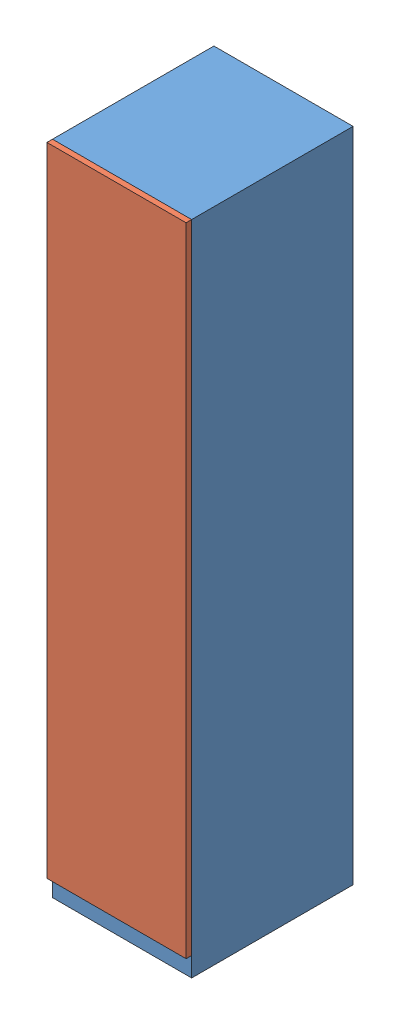
SolidWorks assembly PAX-Eingang, configuration Standard. Lengths in mm.
Overall size (500 2360 600).
8 component instances, 6 part files, 21 mates.
Components (placement in the parent):
- Pax-Korpus-Kleiderschrank-236-1: Pax-Korpus-Kleiderschrank-236 [Standard] at (-247.5936 -1124.7676 2360) size (500 2360 580)
- BALLSTAD-Tür-229-1: BALLSTAD-Tür-229 [Standard] at (-247.5936 90.2324 2650) size (500 2290 20)
- KOMPLEMENT-Regalbode-1: KOMPLEMENT-Regalbode [Standard] at (-247.5936 895.2324 2365) size (480 10 570)
- KOMPLEMENT-Kleiderstange-1: KOMPLEMENT-Kleiderstange [Standard] at (-487.5936 830.2324 2335) size (480 50 30)
- KOMPLEMENT-Regalbode-2: KOMPLEMENT-Regalbode [Standard] at (-247.5936 -434.7676 2365) size (480 10 570)
- KOMPLIMENT-Schublade-1: KOMPLIMENT-Schublade [Standard] at (-247.5936 -604.7676 2365) size (480 160 570)
- KOMPLEMENT-Netzdrahtkorb-1: KOMPLEMENT-Netzdrahtkorb [Standard] at (-247.5936 -894.7676 2365) size (480 160 570)
- KOMPLEMENT-Regalbode-3: KOMPLEMENT-Regalbode [Standard] at (-247.5936 -274.7676 2365) size (480 10 570)
Mates (geometry in assembly coordinates):
- Deckungsgleich1: coincident aligned: plane of Pax-Korpus-Kleiderschrank-236-1 through (-247.5936 1235.2324 2360) normal (0 1 0); plane of BALLSTAD-Tür-229-1 through (-497.5936 1235.2324 2670) normal (0 1 0)
- Deckungsgleich2: coincident anti-aligned: plane of Pax-Korpus-Kleiderschrank-236-1 through (-497.5936 -1114.7676 2650) normal (0 0 1); plane of BALLSTAD-Tür-229-1 through (-247.5936 90.2324 2650) normal (0 0 -1)
- Deckungsgleich3: coincident aligned: plane of Pax-Korpus-Kleiderschrank-236-1 through (-497.5936 -1114.7676 2650) normal (-1 0 0); plane of BALLSTAD-Tür-229-1 through (-497.5936 -1054.7676 2670) normal (-1 0 0)
- Deckungsgleich4: coincident anti-aligned: plane of Pax-Korpus-Kleiderschrank-236-1 through (-487.5936 1225.2324 2080) normal (0 0 1); plane of KOMPLEMENT-Regalbode-1 through (-487.5936 905.2324 2080) normal (0 0 -1)
- Deckungsgleich5: coincident anti-aligned: plane of Pax-Korpus-Kleiderschrank-236-1 through (-487.5936 1225.2324 2650) normal (1 0 0); plane of KOMPLEMENT-Regalbode-1 through (-487.5936 905.2324 2650) normal (-1 0 0)
- Abstand1: distance = 320 mm anti-aligned: plane of KOMPLEMENT-Regalbode-1 through (-247.5936 905.2324 2365) normal (0 1 0); plane of Pax-Korpus-Kleiderschrank-236-1 through (-247.5936 1225.2324 2360) normal (0 -1 0)
- Deckungsgleich7: coincident anti-aligned: plane of Pax-Korpus-Kleiderschrank-236-1 through (-487.5936 1225.2324 2650) normal (1 0 0); plane of KOMPLEMENT-Kleiderstange-1 through (-487.5936 830.2324 2335) normal (-1 0 0)
- Abstand2: distance = 50 mm anti-aligned: plane of KOMPLEMENT-Kleiderstange-1 through (-467.5936 845.2324 2320) normal (0 1 0); plane of KOMPLEMENT-Regalbode-1 through (-247.5936 895.2324 2365) normal (0 -1 0)
- Abstand3: distance = 300 mm aligned: plane of KOMPLEMENT-Kleiderstange-1 through (-467.5936 795.2324 2350) normal (0 0 1); plane of Pax-Korpus-Kleiderschrank-236-1 through (-497.5936 -1114.7676 2650) normal (0 0 1)
- Deckungsgleich10: coincident anti-aligned: plane of Pax-Korpus-Kleiderschrank-236-1 through (-487.5936 1225.2324 2080) normal (0 0 1); plane of KOMPLEMENT-Regalbode-2 through (-487.5936 -424.7676 2080) normal (0 0 -1)
- Deckungsgleich11: coincident anti-aligned: plane of Pax-Korpus-Kleiderschrank-236-1 through (-487.5936 1225.2324 2650) normal (1 0 0); plane of KOMPLEMENT-Regalbode-2 through (-487.5936 -424.7676 2650) normal (-1 0 0)
- Abstand4: distance = 1220 mm anti-aligned: plane of KOMPLEMENT-Kleiderstange-1 through (-467.5936 795.2324 2320) normal (0 -1 0); plane of KOMPLEMENT-Regalbode-2 through (-247.5936 -424.7676 2365) normal (0 1 0)
- Deckungsgleich13: coincident anti-aligned: plane of Pax-Korpus-Kleiderschrank-236-1 through (-487.5936 1225.2324 2080) normal (0 0 1); plane of KOMPLIMENT-Schublade-1 through (-487.5936 -594.7676 2080) normal (0 0 -1)
- Deckungsgleich14: coincident anti-aligned: plane of Pax-Korpus-Kleiderschrank-236-1 through (-487.5936 1225.2324 2650) normal (1 0 0); plane of KOMPLIMENT-Schublade-1 through (-487.5936 -594.7676 2650) normal (-1 0 0)
- Abstand5: distance = 10 mm anti-aligned: plane of KOMPLIMENT-Schublade-1 through (-247.5936 -444.7676 2365) normal (0 1 0); plane of KOMPLEMENT-Regalbode-2 through (-247.5936 -434.7676 2365) normal (0 -1 0)
- Deckungsgleich16: coincident anti-aligned: plane of Pax-Korpus-Kleiderschrank-236-1 through (-247.5936 -1054.7676 2360) normal (0 1 0); plane of KOMPLEMENT-Netzdrahtkorb-1 through (-247.5936 -1054.7676 2365) normal (0 -1 0)
- Deckungsgleich17: coincident: plane of Pax-Korpus-Kleiderschrank-236-1 through (-487.5936 1225.2324 2650) normal (1 0 0); line of KOMPLEMENT-Netzdrahtkorb-1 through (-487.5936 -894.7676 2080) axis (0 0 1)
- Deckungsgleich18: coincident: plane of Pax-Korpus-Kleiderschrank-236-1 through (-487.5936 1225.2324 2080) normal (0 0 1); line of KOMPLEMENT-Netzdrahtkorb-1 through (-7.5936 -894.7676 2080) axis (-1 0 0)
- Deckungsgleich19: coincident anti-aligned: plane of Pax-Korpus-Kleiderschrank-236-1 through (-7.5936 1225.2324 2080) normal (-1 0 0); plane of KOMPLEMENT-Regalbode-3 through (-7.5936 -264.7676 2650) normal (1 0 0)
- Deckungsgleich20: coincident anti-aligned: plane of Pax-Korpus-Kleiderschrank-236-1 through (-487.5936 1225.2324 2080) normal (0 0 1); plane of KOMPLEMENT-Regalbode-3 through (-487.5936 -264.7676 2080) normal (0 0 -1)
- Abstand7: distance = 150 mm anti-aligned: plane of KOMPLEMENT-Regalbode-3 through (-247.5936 -274.7676 2365) normal (0 -1 0); plane of KOMPLEMENT-Regalbode-2 through (-247.5936 -424.7676 2365) normal (0 1 0)
